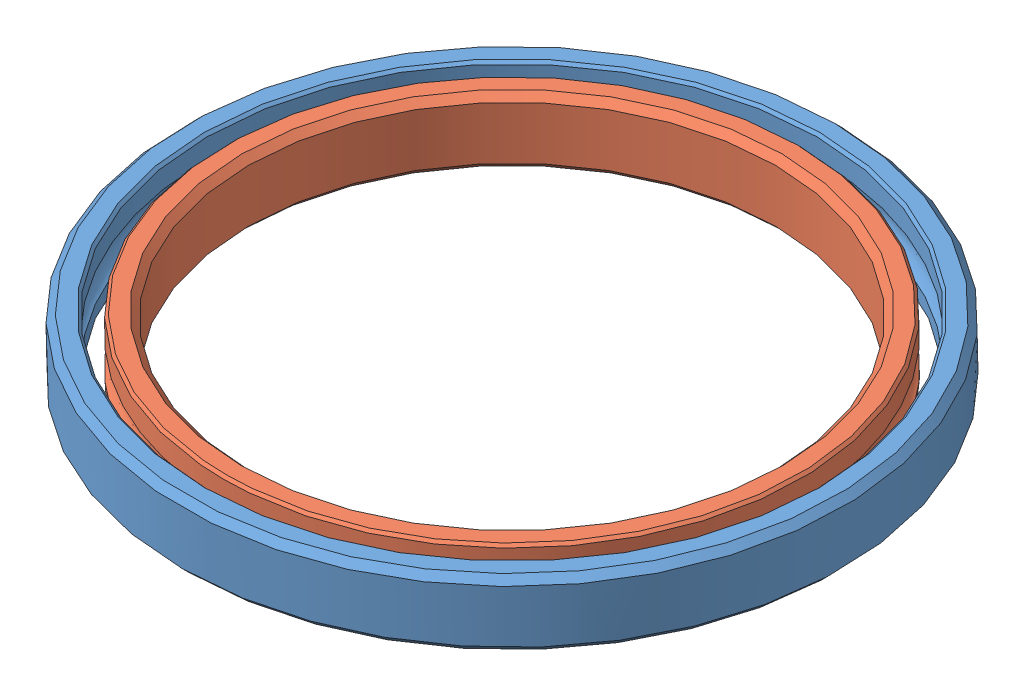
SolidWorks assembly SW3dPS-KA - Radial Contact, configuration KA020CP0. Lengths in mm.
Overall size (63.5 6.35 63.5).
31 component instances, 4 part files, 6 mates.
Components (placement in the parent):
- SW3dPS-KA - Radial Contact_KA OUTER CATALOG-1: SW3dPS-KA - Radial Contact_KA OUTER CATALOG [KA020002] at origin size (63.5 6.35 63.5)
- SW3dPS-KA - Radial Contact_KA INNER CATALOG-1: SW3dPS-KA - Radial Contact_KA INNER CATALOG [KA020003] at origin size (55.52 6.35 55.52)
- SW3dPS-KA - Radial Contact_KA SEPARATOR SAMPLE-1: KA SEPARATOR SAMPLE [KA020] at origin size (60.31 5.28 60.41)
  - KA SEPARATOR SAMPLE-1: KA SEPARATOR SAMPLE [02510020] at origin (suppressed, hidden)
  - KA BALL-1: KA BALL [KA020] at origin (suppressed, hidden)
  - KA BALL-2: KA BALL [KA020] x (0.973045 0 0.230616) z (-0.230616 0 0.973045) (suppressed, hidden)
  - KA BALL-3: KA BALL [KA020] x (0.893633 0 0.448799) z (-0.448799 0 0.893633) (suppressed, hidden)
  - KA BALL-4: KA BALL [KA020] x (0.766044 0 0.642788) z (-0.642788 0 0.766044) (suppressed, hidden)
  - KA BALL-5: KA BALL [KA020] x (0.597159 0 0.802123) z (-0.802123 0 0.597159) (suppressed, hidden)
  - KA BALL-6: KA BALL [KA020] x (0.39608 0 0.918216) z (-0.918216 0 0.39608) (suppressed, hidden)
  - KA BALL-7: KA BALL [KA020] x (0.173648 0 0.984808) z (-0.984808 0 0.173648) (suppressed, hidden)
  - KA BALL-8: KA BALL [KA020] x (-0.058145 0 0.998308) z (-0.998308 0 -0.058145) (suppressed, hidden)
  - KA BALL-9: KA BALL [KA020] x (-0.286803 0 0.95799) z (-0.95799 0 -0.286803) (suppressed, hidden)
  - KA BALL-10: KA BALL [KA020] x (-0.5 0 0.866025) z (-0.866025 0 -0.5) (suppressed, hidden)
  - KA BALL-11: KA BALL [KA020] x (-0.686242 0 0.727374) z (-0.727374 0 -0.686242) (suppressed, hidden)
  - KA BALL-12: KA BALL [KA020] x (-0.835488 0 0.549509) z (-0.549509 0 -0.835488) (suppressed, hidden)
  - KA BALL-13: KA BALL [KA020] x (-0.939693 0 0.34202) z (-0.34202 0 -0.939693) (suppressed, hidden)
  - KA BALL-14: KA BALL [KA020] x (-0.993238 0 0.116093) z (-0.116093 0 -0.993238) (suppressed, hidden)
  - KA BALL-15: KA BALL [KA020] x (-0.993238 0 -0.116093) z (0.116093 0 -0.993238) (suppressed, hidden)
  - KA BALL-16: KA BALL [KA020] x (-0.939693 0 -0.34202) z (0.34202 0 -0.939693) (suppressed, hidden)
  - KA BALL-34: KA BALL [KA020] x (-0.835488 0 -0.549509) z (0.549509 0 -0.835488) (suppressed, hidden)
  - KA BALL-35: KA BALL [KA020] x (-0.686242 0 -0.727374) z (0.727374 0 -0.686242) (suppressed, hidden)
  - KA BALL-36: KA BALL [KA020] x (-0.5 0 -0.866025) z (0.866025 0 -0.5) (suppressed, hidden)
  - KA BALL-37: KA BALL [KA020] x (-0.286803 0 -0.95799) z (0.95799 0 -0.286803) (suppressed, hidden)
  - KA BALL-38: KA BALL [KA020] x (-0.058145 0 -0.998308) z (0.998308 0 -0.058145) (suppressed, hidden)
  - KA BALL-39: KA BALL [KA020] x (0.173648 0 -0.984808) z (0.984808 0 0.173648) (suppressed, hidden)
  - KA BALL-40: KA BALL [KA020] x (0.39608 0 -0.918216) z (0.918216 0 0.39608) (suppressed, hidden)
  - KA BALL-41: KA BALL [KA020] x (0.597159 0 -0.802123) z (0.802123 0 0.597159) (suppressed, hidden)
  - KA BALL-42: KA BALL [KA020] x (0.766044 0 -0.642788) z (0.642788 0 0.766044) (suppressed, hidden)
  - KA BALL-43: KA BALL [KA020] x (0.893633 0 -0.448799) z (0.448799 0 0.893633) (suppressed, hidden)
  - KA BALL-44: KA BALL [KA020] x (0.973045 0 -0.230616) z (0.230616 0 0.973045) (suppressed, hidden)
Mates (geometry in assembly coordinates):
- Concentric1: concentric anti-aligned: cylinder of SW3dPS-KA - Radial Contact_KA OUTER CATALOG-1; cylinder of SW3dPS-KA - Radial Contact_KA INNER CATALOG-1
- Coincident1: coincident: point of SW3dPS-KA - Radial Contact_KA INNER CATALOG-1; point of assembly
- Coincident2: coincident aligned: plane of SW3dPS-KA - Radial Contact_KA INNER CATALOG-1; plane of assembly
- Concentric2: concentric anti-aligned: cylinder of SW3dPS-KA - Radial Contact_KA OUTER CATALOG-1; cylinder of SW3dPS-KA - Radial Contact_KA SEPARATOR SAMPLE-1/KA SEPARATOR SAMPLE-1
- Coincident4: coincident: point of ?; point of assembly
- Coincident5: coincident aligned: plane of ?; plane of assembly
